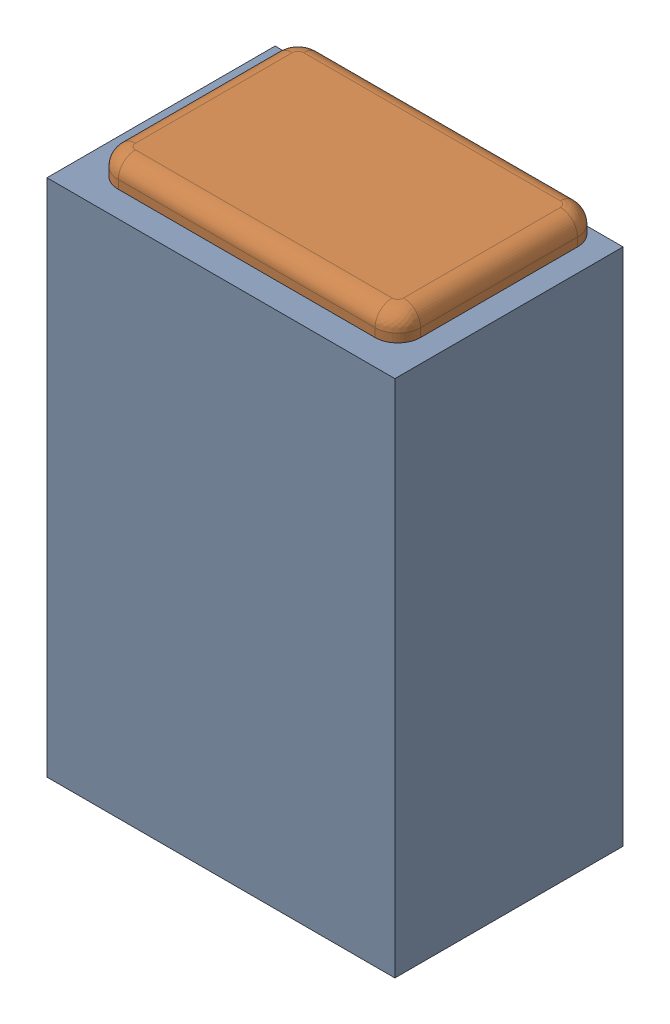
SolidWorks assembly C3, configuration Default. Lengths in mm.
Overall size (0.61 1 0.4).
3 component instances, 2 part files, 0 mates.
Components (placement in the parent):
- 1088881848-1: 1088881848 [Default] at (10.375 41.25 0) size (0.61 0.91 0.4)
  - Extruded-1-1: Extruded-1 [Default] at origin size (0.61 0.91 0.4)
- C0402-1: C0402 [Default] at (10.3751 41.2499 0) x (0 -1 0) z (-1 0 0) size (1 0.36 0.54)
